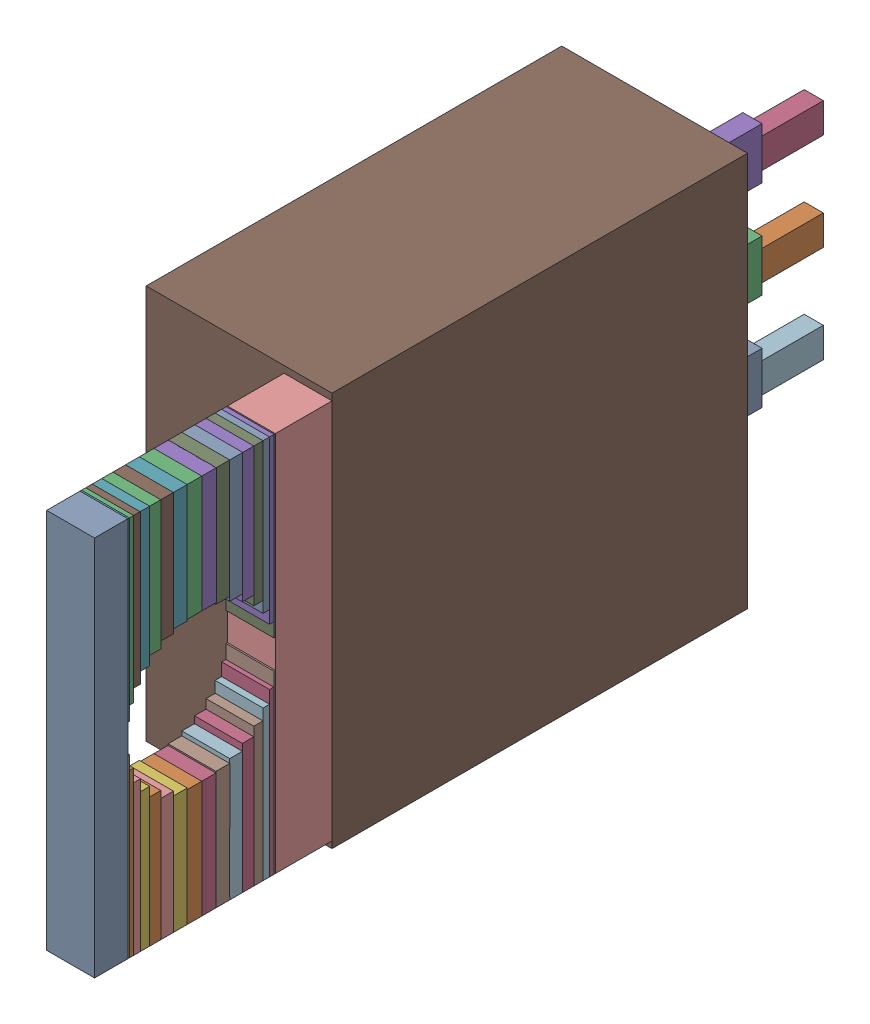
SolidWorks assembly Q5.step, configuration Default. Lengths in mm.
Overall size (4.85 10.3 21.45).
82 component instances, 18 part files, 0 mates.
Components (placement in the parent):
- 6100337184.step-1: 6100337184.step [Default] at (105.55 30.861 18.98) size (1.25 9.95 0.87)
  - Extruded.step-1: Extruded.step [Default] at origin size (1.25 9.95 0.87)
- 6100336784.step-1: 6100336784.step [Default] at (105.55 27.411 17.05) size (1.25 3.05 0.38)
  - Extruded-8.step-1: Extruded-8.step [Default] at origin size (1.25 3.05 0.38)
- 6100336784.step-2: 6100336784.step [Default] at (105.55 34.311 17.05) size (1.25 3.05 0.38)
  - Extruded-8.step-1: Extruded-8.step [Default] at origin size (1.25 3.05 0.38)
- 6100335504.step-1: 6100335504.step [Default] at (105.55 27.411 16.67) size (1.25 3.05 0.38)
  - Extruded-9.step-1: Extruded-9.step [Default] at origin size (1.25 3.05 0.38)
- 6100335504.step-2: 6100335504.step [Default] at (105.55 34.311 16.67) size (1.25 3.05 0.38)
  - Extruded-9.step-1: Extruded-9.step [Default] at origin size (1.25 3.05 0.38)
- 6100342224.step-1: 6100342224.step [Default] at (105.55 27.4295 17.43) size (1.25 3.09 0.36)
  - Extruded-10.step-1: Extruded-10.step [Default] at origin size (1.25 3.09 0.36)
- 6100342224.step-2: 6100342224.step [Default] at (105.55 34.2925 17.43) size (1.25 3.09 0.36)
  - Extruded-10.step-1: Extruded-10.step [Default] at origin size (1.25 3.09 0.36)
- 6100331024.step-1: 6100331024.step [Default] at (105.55 27.4295 16.31) size (1.25 3.09 0.37)
  - Extruded-11.step-1: Extruded-11.step [Default] at origin size (1.25 3.09 0.37)
- 6100331024.step-2: 6100331024.step [Default] at (105.55 34.2925 16.31) size (1.25 3.09 0.37)
  - Extruded-11.step-1: Extruded-11.step [Default] at origin size (1.25 3.09 0.37)
- 6100330544.step-1: 6100330544.step [Default] at (105.55 27.4843 17.79) size (1.25 3.2 0.33)
  - Extruded-12.step-1: Extruded-12.step [Default] at origin size (1.25 3.2 0.33)
- 6100330544.step-2: 6100330544.step [Default] at (105.55 34.2377 17.79) size (1.25 3.2 0.33)
  - Extruded-12.step-1: Extruded-12.step [Default] at origin size (1.25 3.2 0.33)
- 6100330224.step-1: 6100330224.step [Default] at (105.55 27.4843 15.98) size (1.25 3.2 0.34)
  - Extruded-13.step-1: Extruded-13.step [Default] at origin size (1.25 3.2 0.34)
- 6100330224.step-2: 6100330224.step [Default] at (105.55 34.2377 15.98) size (1.25 3.2 0.34)
  - Extruded-13.step-1: Extruded-13.step [Default] at origin size (1.25 3.2 0.34)
- 6100325984.step-1: 6100325984.step [Default] at (105.55 27.5732 18.12) size (1.25 3.37 0.3)
  - Extruded-14.step-1: Extruded-14.step [Default] at origin size (1.25 3.37 0.3)
- 6100325984.step-2: 6100325984.step [Default] at (105.55 34.1488 18.12) size (1.25 3.37 0.3)
  - Extruded-14.step-1: Extruded-14.step [Default] at origin size (1.25 3.37 0.3)
- 6100325984.step-3: 6100325984.step [Default] at (105.55 27.5732 15.69) size (1.25 3.37 0.3)
  - Extruded-14.step-1: Extruded-14.step [Default] at origin size (1.25 3.37 0.3)
- 6100325984.step-4: 6100325984.step [Default] at (105.55 34.1488 15.69) size (1.25 3.37 0.3)
  - Extruded-14.step-1: Extruded-14.step [Default] at origin size (1.25 3.37 0.3)
- 6100325824.step-1: 6100325824.step [Default] at (105.55 27.6929 18.41) size (1.25 3.61 0.25)
  - Extruded-15.step-1: Extruded-15.step [Default] at origin size (1.25 3.61 0.25)
- 6100325824.step-2: 6100325824.step [Default] at (105.55 34.0291 18.41) size (1.25 3.61 0.25)
  - Extruded-15.step-1: Extruded-15.step [Default] at origin size (1.25 3.61 0.25)
- 6100326864.step-1: 6100326864.step [Default] at (105.55 27.6929 15.45) size (1.25 3.61 0.24)
  - Extruded-16.step-1: Extruded-16.step [Default] at origin size (1.25 3.61 0.24)
- 6100326864.step-2: 6100326864.step [Default] at (105.55 34.0291 15.45) size (1.25 3.61 0.24)
  - Extruded-16.step-1: Extruded-16.step [Default] at origin size (1.25 3.61 0.24)
- 6100326304.step-1: 6100326304.step [Default] at (105.55 27.8388 18.65) size (1.25 3.91 0.18)
  - Extruded-17.step-1: Extruded-17.step [Default] at origin size (1.25 3.91 0.18)
- 6100326304.step-2: 6100326304.step [Default] at (105.55 33.8832 18.65) size (1.25 3.91 0.18)
  - Extruded-17.step-1: Extruded-17.step [Default] at origin size (1.25 3.91 0.18)
- 6100326304.step-3: 6100326304.step [Default] at (105.55 27.8388 15.27) size (1.25 3.91 0.18)
  - Extruded-17.step-1: Extruded-17.step [Default] at origin size (1.25 3.91 0.18)
- 6100326304.step-4: 6100326304.step [Default] at (105.55 33.8832 15.27) size (1.25 3.91 0.18)
  - Extruded-17.step-1: Extruded-17.step [Default] at origin size (1.25 3.91 0.18)
- 6100326704.step-1: 6100326704.step [Default] at (105.55 28.0052 18.83) size (1.25 4.24 0.11)
  - Extruded-18.step-1: Extruded-18.step [Default] at origin size (1.25 4.24 0.11)
- 6100326704.step-2: 6100326704.step [Default] at (105.55 33.7168 18.83) size (1.25 4.24 0.11)
  - Extruded-18.step-1: Extruded-18.step [Default] at origin size (1.25 4.24 0.11)
- 6100327504.step-1: 6100327504.step [Default] at (105.55 28.0052 15.16) size (1.25 4.24 0.12)
  - Extruded-19.step-1: Extruded-19.step [Default] at origin size (1.25 4.24 0.12)
- 6100327504.step-2: 6100327504.step [Default] at (105.55 33.7168 15.16) size (1.25 4.24 0.12)
  - Extruded-19.step-1: Extruded-19.step [Default] at origin size (1.25 4.24 0.12)
- 6100327344.step-1: 6100327344.step [Default] at (105.55 28.1857 18.94) size (1.25 4.6 0.04)
  - Extruded-20.step-1: Extruded-20.step [Default] at origin size (1.25 4.6 0.04)
- 6100327344.step-2: 6100327344.step [Default] at (105.55 33.5363 18.94) size (1.25 4.6 0.04)
  - Extruded-20.step-1: Extruded-20.step [Default] at origin size (1.25 4.6 0.04)
- 6100327344.step-3: 6100327344.step [Default] at (105.55 28.1857 15.13) size (1.25 4.6 0.04)
  - Extruded-20.step-1: Extruded-20.step [Default] at origin size (1.25 4.6 0.04)
- 6100327344.step-4: 6100327344.step [Default] at (105.55 33.5363 15.13) size (1.25 4.6 0.04)
  - Extruded-20.step-1: Extruded-20.step [Default] at origin size (1.25 4.6 0.04)
- 6100330864.step-1: 6100330864.step [Default] at (105.55 30.861 13.65) size (1.25 9.95 1.48)
  - Extruded-21.step-1: Extruded-21.step [Default] at origin size (1.25 9.95 1.48)
- 6100331424.step-1: 6100331424.step [Default] at (103.75 30.861 2.8) size (4.85 10.3 10.85)
  - Extruded-22.step-1: Extruded-22.step [Default] at origin size (4.85 10.3 10.85)
- 6100325584.step-1: 6100325584.step [Default] at (103.505 28.321 -1.6) size (0.5 0.78 1.6)
  - Extruded-23.step-1: Extruded-23.step [Default] at origin size (0.5 0.78 1.6)
- 6138241984.step-1: 6138241984.step [Default] at (103.505 28.321 0) size (0.5 1.34 2.8)
  - Extruded-24.step-1: Extruded-24.step [Default] at origin size (0.5 1.34 2.8)
- 6100325584.step-2: 6100325584.step [Default] at (103.505 30.861 -1.6) size (0.5 0.78 1.6)
  - Extruded-23.step-1: Extruded-23.step [Default] at origin size (0.5 0.78 1.6)
- 6138241984.step-2: 6138241984.step [Default] at (103.505 30.861 0) size (0.5 1.34 2.8)
  - Extruded-24.step-1: Extruded-24.step [Default] at origin size (0.5 1.34 2.8)
- 6100325584.step-3: 6100325584.step [Default] at (103.505 33.401 -1.6) size (0.5 0.78 1.6)
  - Extruded-23.step-1: Extruded-23.step [Default] at origin size (0.5 0.78 1.6)
- 6138241984.step-3: 6138241984.step [Default] at (103.505 33.401 0) size (0.5 1.34 2.8)
  - Extruded-24.step-1: Extruded-24.step [Default] at origin size (0.5 1.34 2.8)
